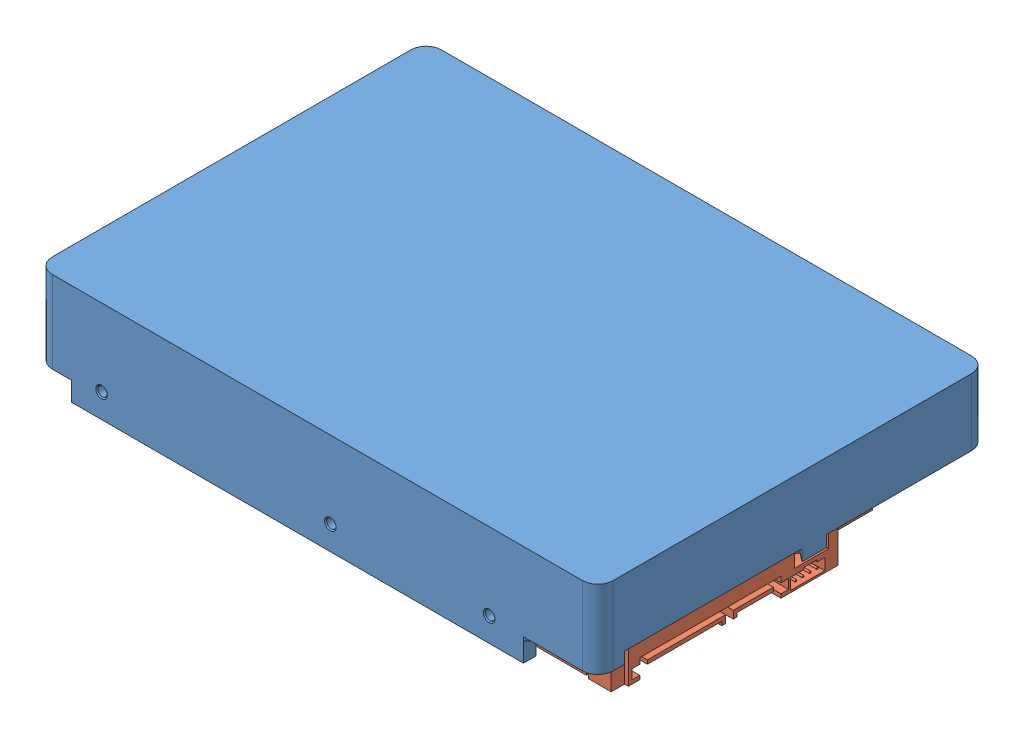
SolidWorks assembly 3_5寸硬盘装配体, configuration 默认. Lengths in mm.
Overall size (147 26.5 102).
2 component instances, 2 part files, 2 mates.
Components (placement in the parent):
- 3_5寸硬盘-1: 3_5寸硬盘 [默认] at (-8.1461 -11.3906 147) size (147 26.5 102)
- 3_5寸硬盘主板-1: 3_5寸硬盘主板 [默认] at (-0.6461 -10.3906 193.5) size (66 8.5 81)
Mates (geometry in assembly coordinates):
- 重合1: coincident anti-aligned: plane of 3_5寸硬盘-1 through (8.8539 -9.3906 156.5) normal (0 -1 0); plane of 3_5寸硬盘主板-1 through (-0.6461 -9.3906 193.5) normal (0 1 0)
- 同心1: concentric anti-aligned: circle of 3_5寸硬盘-1; cylinder of 3_5寸硬盘主板-1 through (24.0739 -10.8906 194.5) axis (0 1 0) radius 4.5
